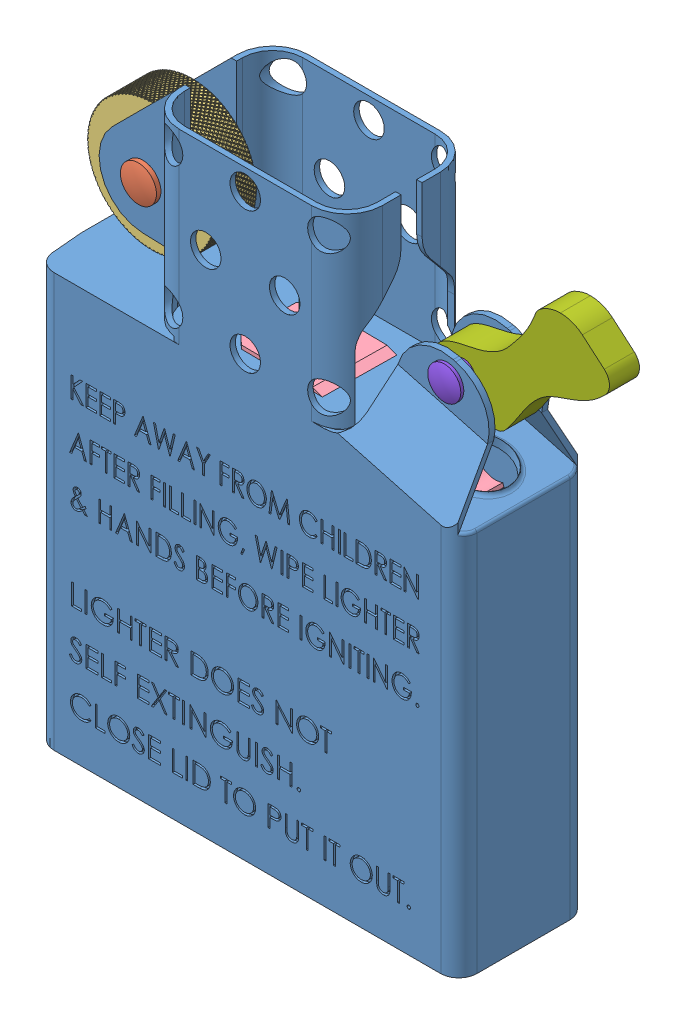
SolidWorks assembly ZLSA-1, configuration Default. Lengths in mm.
Overall size (46.06 52.1 10.92).
8 component instances, 8 part files, 15 mates.
Components (placement in the parent):
- ZLSAP-101 INNER BODY  final-1: ZLSAP-101 INNER BODY  final [Default] at (-7.9372 -6.5366 -12.4236) size (36.03 50.8 10.92)
- ZLSAP- 103 FLINT WHEEL RIVET-1: ZLSAP- 103 FLINT WHEEL RIVET [Default] at (-2.0952 35.9322 -20.3738) x (0.999904 -0.013836 0) z (0 0 1) size (3.05 3.05 5.61)
- ZLSAP-102 FLINT WHEEL-1: ZLSAP-102 FLINT WHEEL [Default] at (-2.0952 35.9322 -19.6118) x (0.403871 -0.914816 0) z (0 0 1) size (10.96 10.96 3.56)
- ZLSAP-104 CAM SPRING-2: ZLSAP-104 CAM SPRING [Default] at (6.0886 28.617 -17.8658) x (0.999917 0 0.012886) z (0.012886 0 -0.999917) size (18.35 4.12 6.22)
- ZLSAP-108 EYELET-1: ZLSAP-108 EYELET [Default] at (9.5562 26.2294 -17.8846) x (-0.386007 0 0.922496) z (0 1 0) size (4.57 4.57 2.79)
- ZLSAP-107 WICK-1: ZLSAP-107 WICK [Default] at (9.5562 32.8921 -17.8846) x (-0.99856 0 0.053653) z (0 -1 0) size (1.28 1.29 20.32)
- ZLSAP-105 CAM-1: ZLSAP-105 CAM [Default] at (27.9448 37.59 -16.7416) x (-0.85034 0.526234 0) z (0 0 -1) size (10.34 13.18 2.54)
- ZLSAP-106 CAM RIVET PIN-1: ZLSAP-106 CAM RIVET PIN [Default] at (23.7253 34.2136 -20.6278) x (-0.237452 -0.971399 0) z (0 0 1) size (2.79 2.79 5.87)
Mates (geometry in assembly coordinates):
- Concentric8: concentric anti-aligned: circle of ZLSAP-101 INNER BODY  final-1; circle of ZLSAP-104 CAM SPRING-2
- Concentric9: concentric anti-aligned: circle of ZLSAP-101 INNER BODY  final-1; circle of ZLSAP-104 CAM SPRING-2
- Coincident7: coincident anti-aligned: plane of ZLSAP-101 INNER BODY  final-1 through (23.3397 28.4646 -17.8846) normal (0 1 0); plane of ZLSAP-104 CAM SPRING-2 through (6.1287 28.4646 -20.977) normal (0 -1 0)
- Concentric10: concentric anti-aligned: circle of ZLSAP-104 CAM SPRING-2; circle of ZLSAP-108 EYELET-1
- Coincident9: coincident anti-aligned: plane of ZLSAP-104 CAM SPRING-2 through (6.1287 28.7694 -20.977) normal (0 1 0); plane of ZLSAP-108 EYELET-1 through (9.5562 28.7694 -17.8846) normal (0 -1 0)
- Concentric11: concentric aligned: cylinder of ZLSAP-108 EYELET-1 through (9.5562 29.0234 -17.8846) axis (0 -1 0) radius 1.2446; circle of ZLSAP-107 WICK-1
- Concentric12: concentric aligned: circle of ZLSAP-101 INNER BODY  final-1; circle of ZLSAP-102 FLINT WHEEL-1
- Concentric14: concentric anti-aligned: cylinder of ZLSAP-101 INNER BODY  final-1 through (-2.0952 35.9322 -25.5808) axis (0 0 1) radius 1.4732; cylinder of ZLSAP- 103 FLINT WHEEL RIVET-1 through (-2.0952 35.9322 -15.4208) axis (0 0 -1) radius 1.0795
- Coincident12: coincident anti-aligned: plane of ZLSAP-101 INNER BODY  final-1 through (-7.9372 44.2634 -15.4208) normal (0 0 1); plane of ZLSAP- 103 FLINT WHEEL RIVET-1 through (-2.0952 35.9322 -15.4208) normal (0 0 -1)
- Width1: width anti-aligned: plane of ZLSAP-105 CAM-1 through (30.4965 35.7417 -16.7416) normal (0 0 1); plane of ZLSAP-106 CAM RIVET PIN-1 through (30.4965 35.7417 -19.2816) normal (0 0 -1); plane of ZLSAP-105 CAM-1 through (23.7253 34.2136 -20.6786) normal (0 0 -1); plane of ZLSAP-106 CAM RIVET PIN-1 through (23.7253 34.2136 -15.3446) normal (0 0 -1)
- Concentric21: concentric aligned: cylinder of ZLSAP-105 CAM-1 through (23.7253 34.2136 -19.2816) axis (0 0 -1) radius 0.9652; cylinder of ZLSAP-106 CAM RIVET PIN-1 through (23.7253 34.2136 -15.3446) axis (0 0 -1) radius 0.9652
- Concentric22: concentric anti-aligned: cylinder of ZLSAP-101 INNER BODY  final-1 through (23.7253 34.2136 -23.3456) axis (0 0 1) radius 0.9779; cylinder of ZLSAP-106 CAM RIVET PIN-1 through (23.7253 34.2136 -15.3446) axis (0 0 -1) radius 0.9652
- Coincident17: coincident anti-aligned: plane of ZLSAP-101 INNER BODY  final-1 through (20.5443 37.0467 -15.3446) normal (0 0 1); plane of ZLSAP-106 CAM RIVET PIN-1 through (23.7253 34.2136 -15.3446) normal (0 0 -1)
- Concentric24: concentric anti-aligned: cylinder of ZLSAP- 103 FLINT WHEEL RIVET-1 through (-2.0952 35.9322 -15.4208) axis (0 0 -1) radius 1.0795; circle of ZLSAP-102 FLINT WHEEL-1
- Width2: width aligned: plane of ZLSAP-102 FLINT WHEEL-1 through (-2.0952 35.9322 -16.1574) normal (0 0 1); plane of ZLSAP-101 INNER BODY  final-1 through (-2.0952 35.9322 -19.6118) normal (0 0 -1); plane of ZLSAP-102 FLINT WHEEL-1 through (3.4928 -6.5366 -19.8404) normal (0 0 1); plane of ZLSAP-101 INNER BODY  final-1 through (3.4928 -6.5366 -15.9288) normal (0 0 -1)
